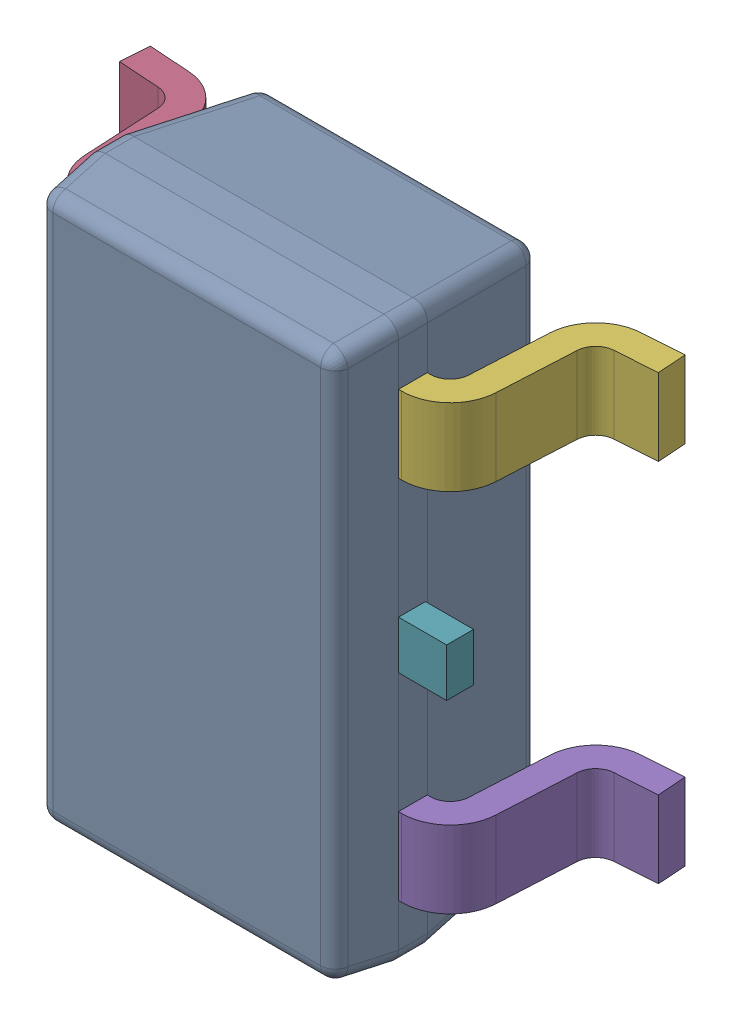
SolidWorks assembly 6348793248_1.step, configuration Default. Lengths in mm.
Overall size (2.8 2.9 1.2).
7 component instances, 3 part files, 0 mates.
Components (placement in the parent):
- BODY-SOT_1.step-3: BODY-SOT_1.step [Default] at (0 0 0.9) x (0 -1 0) z (-1 0 0) size (2.9 1.1 1.6)
- LEAD-SOT_1.step-11: LEAD-SOT_1.step [Default] at (-0.9395 -0.95 0.25) x (0 -1 0) z (-1 0 0) size (0.4 0.9 0.6)
- LEAD-SOT_1.step-12: LEAD-SOT_1.step [Default] at (-0.9395 0 0.25) x (0 -1 0) z (-1 0 0) size (0.4 0.9 0.6)
- LEAD-SOT_1.step-13: LEAD-SOT_1.step [Default] at (-0.9395 0.95 0.25) x (0 -1 0) z (-1 0 0) size (0.4 0.9 0.6)
- LEAD-SOT_1.step-14: LEAD-SOT_1.step [Default] at (0.9395 -0.95 0.25) x (0 1 0) z (1 0 0) size (0.4 0.9 0.6)
- LEAD-SOT_1.step-15: LEAD-SOT_1.step [Default] at (0.9395 0.95 0.25) x (0 1 0) z (1 0 0) size (0.4 0.9 0.6)
- LEAD-DUMMY_1.step-3: LEAD-DUMMY_1.step [Default] at (1.05 0 0.76) x (0 -1 0) z (-1 0 0) size (0.25 0.14 0.25)
